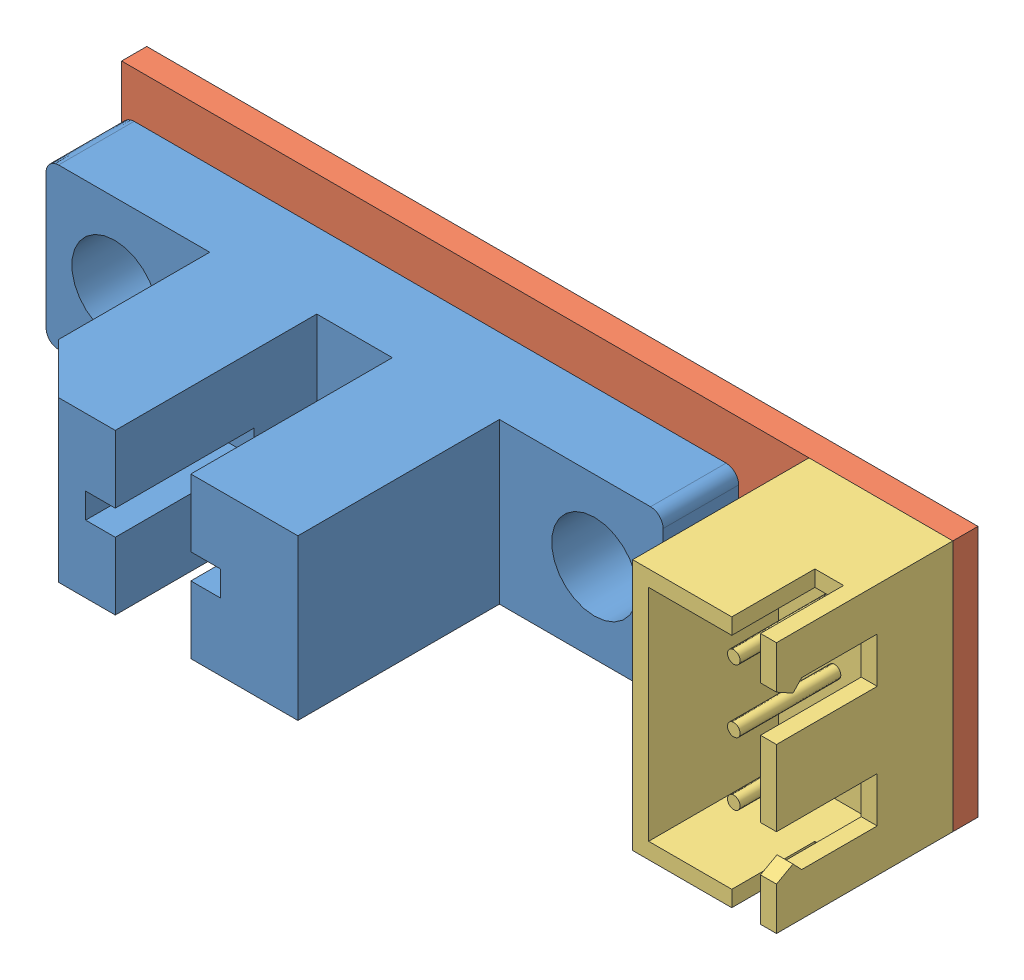
SolidWorks assembly Endstop_Opto_TCST2103, configuration Défaut. Lengths in mm.
Overall size (33 10 12.66).
3 component instances, 3 part files, 15 mates.
Components (placement in the parent):
- TCST2103^Endstop_Opto_TCST2103-1: TCST2103^Endstop_Opto_TCST2103 [Défaut] x (1 0 0) z (0 1 0) size (24.5 11 6.35) (virtual)
- PCB^Endstop_Opto_TCST2103-1: PCB^Endstop_Opto_TCST2103 [Défaut] x (1 0 0) z (0 0 -1) size (33 10 1) (virtual)
- Connector^Endstop_Opto_TCST2103-1: Connector^Endstop_Opto_TCST2103 [Défaut] at (0 -0.6992 0) size (5.71 10 8.66) (virtual)
Mates (geometry in assembly coordinates):
- Sur place1: in place: plane of TCST2103^Endstop_Opto_TCST2103-1 through (0 0 0) normal (0 1 0); moOrthogonalPlaneRef_w of TCST2103^Endstop_Opto_TCST2103-1 through (0 0 0) normal (0 0 -1); line of TCST2103^Endstop_Opto_TCST2103-1 through (55 -55 0) axis (0 0 1); unknown of TCST2103^Endstop_Opto_TCST2103-1
- Coïncidente1: coincident aligned: plane of assembly through (0 0 0) normal (0 1 0); plane of assembly through (0 0 0) normal (0 1 0)
- Coïncidente2: coincident aligned: plane of TCST2103^Endstop_Opto_TCST2103-1 through (0 0 0) normal (0 0 -1)
- Coïncidente3: coincident anti-aligned: plane of TCST2103^Endstop_Opto_TCST2103-1 through (0 0 0) normal (1 0 0)
- Sur place2: in place: plane of TCST2103^Endstop_Opto_TCST2103-1 through (-12.25 3.175 0) normal (0 0 -1); plane of ? through (0 0 0) normal (0 0 -1); plane of TCST2103^Endstop_Opto_TCST2103-1 through (-12.25 3.175 0) normal (0 0 -1); line of ? through (-55 0 0) axis (0 0 1); plane of TCST2103^Endstop_Opto_TCST2103-1 through (-12.25 3.175 0) normal (0 0 -1); plane of ? through (0 0 0) normal (-1 0 0); plane of TCST2103^Endstop_Opto_TCST2103-1 through (-12.25 3.175 0) normal (0 0 -1); unknown of PCB^Endstop_Opto_TCST2103-1
- Coïncidente4: coincident aligned: plane of TCST2103^Endstop_Opto_TCST2103-1; plane of PCB^Endstop_Opto_TCST2103-1
- Coïncidente5: coincident aligned: moOrthogonalPlaneRef_w of TCST2103^Endstop_Opto_TCST2103-1 through (0 0 0) normal (0 -1 0); plane of PCB^Endstop_Opto_TCST2103-1 through (0 0 0) normal (0 -1 0)
- Coïncidente6: coincident anti-aligned: moOrthogonalPlaneRef_w of TCST2103^Endstop_Opto_TCST2103-1 through (0 0 0) normal (-1 0 0); plane of PCB^Endstop_Opto_TCST2103-1 through (0 0 0) normal (1 0 0)
- Sur place3: in place: plane of PCB^Endstop_Opto_TCST2103-1 through (0 0 -1) normal (0 0 -1); plane of ? through (0 0 -1) normal (0 0 -1); plane of PCB^Endstop_Opto_TCST2103-1 through (0 0 -1) normal (0 0 -1); unknown of ?; plane of PCB^Endstop_Opto_TCST2103-1 through (0 0 -1) normal (0 0 -1); plane of ? through (0 0 -1) normal (-1 0 0); plane of PCB^Endstop_Opto_TCST2103-1 through (0 0 -1) normal (0 0 -1); unknown of Connector^Endstop_Opto_TCST2103-1
- Coïncidente7: coincident aligned: plane of PCB^Endstop_Opto_TCST2103-1; plane of Connector^Endstop_Opto_TCST2103-1
- Coïncidente8: coincident aligned: moOrthogonalPlaneRef_w of PCB^Endstop_Opto_TCST2103-1 through (0 0 -1) normal (0 -1 0); plane of Connector^Endstop_Opto_TCST2103-1 through (0 -0.6992 0) normal (0 1 0)
- Coïncidente9: coincident anti-aligned: moOrthogonalPlaneRef_w of PCB^Endstop_Opto_TCST2103-1 through (0 0 -1) normal (-1 0 0); plane of Connector^Endstop_Opto_TCST2103-1 through (0 -0.6992 0) normal (1 0 0)
- Coincident7: coincident aligned: plane of PCB^Endstop_Opto_TCST2103-1 through (20.75 5 -1) normal (1 0 0); plane of Connector^Endstop_Opto_TCST2103-1 through (20.75 5 7) normal (1 0 0)
- Coincident8: coincident aligned: plane of PCB^Endstop_Opto_TCST2103-1 through (-12.25 5 -1) normal (0 1 0); plane of Connector^Endstop_Opto_TCST2103-1 through (20.75 5 7) normal (0 1 0)
- Coincident9: coincident anti-aligned: plane of PCB^Endstop_Opto_TCST2103-1 through (0 0 0) normal (0 0 1); plane of Connector^Endstop_Opto_TCST2103-1 through (0 -0.6992 0) normal (0 0 -1)
